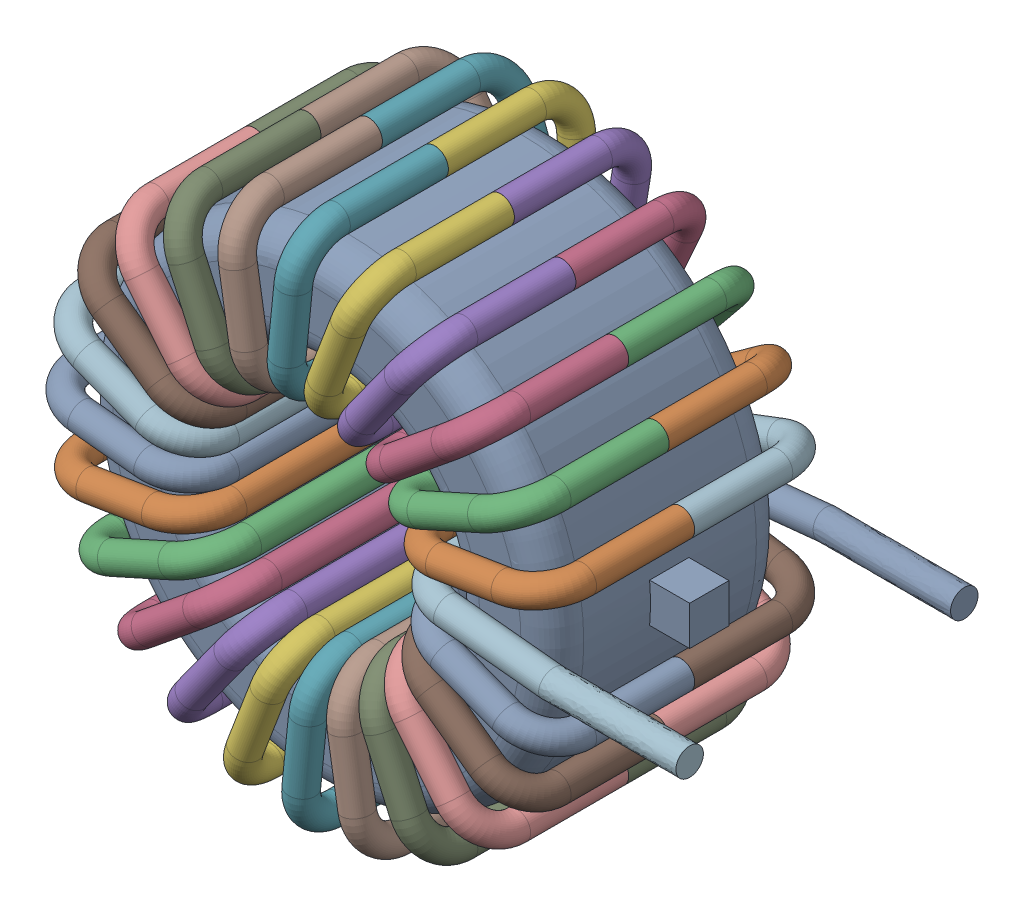
SolidWorks assembly Coil v9_1.step, configuration Default. Lengths in mm.
Overall size (17.32 14.29 7.7).
25 component instances, 4 part files, 0 mates.
Components (placement in the parent):
- Toro_1.step-2: Toro_1.step [Default] at (0.4 28 -5) size (13 12 6)
- Spira_1.step-42: Spira_1.step [Default] at (0.4 28 -5) x (0.965926 0.258819 0) z (0 0 1) size (4.37 2.38 7.7)
- Spira_1.step-43: Spira_1.step [Default] at (0.4 28 -5) x (0.866025 0.5 0) z (0 0 1) size (4.37 2.38 7.7)
- Spira_1.step-45: Spira_1.step [Default] at (0.4 28 -5) x (0.707107 0.707107 0) z (0 0 1) size (4.37 2.38 7.7)
- Spira_1.step-46: Spira_1.step [Default] at (0.4 28 -5) x (0.5 0.866025 0) z (0 0 1) size (4.37 2.38 7.7)
- Spira_1.step-47: Spira_1.step [Default] at (0.4 28 -5) x (0.258819 0.965926 0) z (0 0 1) size (4.37 2.38 7.7)
- Spira_1.step-48: Spira_1.step [Default] at (0.4 28 -5) x (0 1 0) z (0 0 1) size (4.37 2.38 7.7)
- Spira_1.step-49: Spira_1.step [Default] at (0.4 28 -5) x (-0.258819 0.965926 0) z (0 0 1) size (4.37 2.38 7.7)
- Spira_1.step-50: Spira_1.step [Default] at (0.4 28 -5) x (-0.5 0.866025 0) z (0 0 1) size (4.37 2.38 7.7)
- Spira_1.step-51: Spira_1.step [Default] at (0.4 28 -5) x (-0.707107 0.707107 0) z (0 0 1) size (4.37 2.38 7.7)
- Spira_1.step-52: Spira_1.step [Default] at (0.4 28 -5) x (-0.866025 0.5 0) z (0 0 1) size (4.37 2.38 7.7)
- Spira_1.step-53: Spira_1.step [Default] at (0.4 28 -5) x (-0.965926 0.258819 0) z (0 0 1) size (4.37 2.38 7.7)
- Spira_1.step-54: Spira_1.step [Default] at (0.4 28 -5) x (-1 0 0) z (0 0 1) size (4.37 2.38 7.7)
- Spira_1.step-55: Spira_1.step [Default] at (0.4 28 -5) x (-0.965926 -0.258819 0) z (0 0 1) size (4.37 2.38 7.7)
- Spira_1.step-56: Spira_1.step [Default] at (0.4 28 -5) x (-0.866025 -0.5 0) z (0 0 1) size (4.37 2.38 7.7)
- Spira_1.step-57: Spira_1.step [Default] at (0.4 28 -5) x (-0.707107 -0.707107 0) z (0 0 1) size (4.37 2.38 7.7)
- Spira_1.step-58: Spira_1.step [Default] at (0.4 28 -5) x (-0.5 -0.866025 0) z (0 0 1) size (4.37 2.38 7.7)
- Spira_1.step-59: Spira_1.step [Default] at (0.4 28 -5) x (-0.258819 -0.965926 0) z (0 0 1) size (4.37 2.38 7.7)
- Spira_1.step-60: Spira_1.step [Default] at (0.4 28 -5) x (0 -1 0) z (0 0 1) size (4.37 2.38 7.7)
- Spira_1.step-61: Spira_1.step [Default] at (0.4 28 -5) x (0.258819 -0.965926 0) z (0 0 1) size (4.37 2.38 7.7)
- Spira_1.step-62: Spira_1.step [Default] at (0.4 28 -5) x (0.5 -0.866025 0) z (0 0 1) size (4.37 2.38 7.7)
- Spira_1.step-63: Spira_1.step [Default] at (0.4 28 -5) x (0.707107 -0.707107 0) z (0 0 1) size (4.37 2.38 7.7)
- Spira_1.step-64: Spira_1.step [Default] at (0.4 28 -5) x (0.866025 -0.5 0) z (0 0 1) size (4.37 2.38 7.7)
- SpiraCodA_1.step-2: SpiraCodA_1.step [Default] at (0.4015 27.9945 -5) x (1 0.000874 0) z (0 0 1) size (7.52 2.39 7.7)
- SpiraCpdB_1.step-2: SpiraCpdB_1.step [Default] at (0.399 27.9963 -5) x (0.966079 -0.258245 0) z (0 0 1) size (7.28 3.27 7.7)
